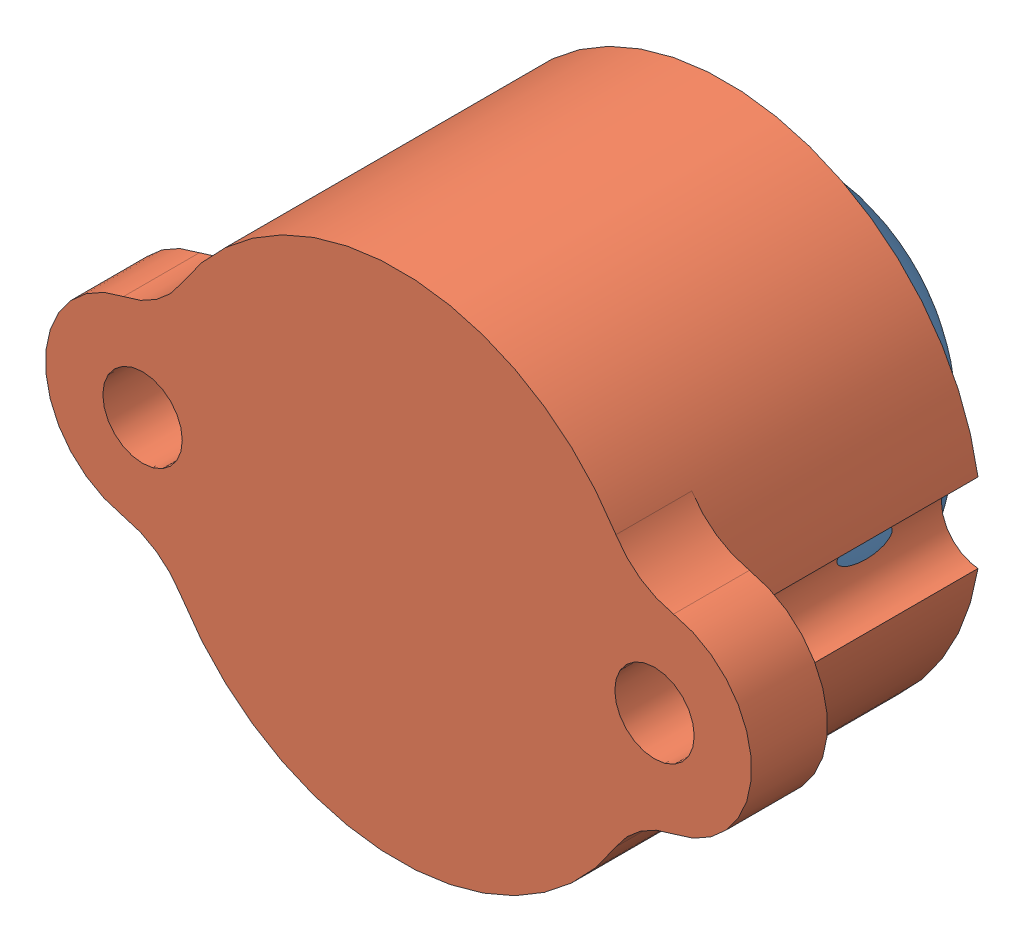
SolidWorks assembly sroller, configuration Default. Lengths in mm.
Overall size (20.32 14.73 13.46).
2 component instances, 2 part files, 1 mates.
Components (placement in the parent):
- boule scroller-1: boule scroller [Default] at (-35.481 -6.7783 23.3279) size (12.55 12.55 12.55)
- scroll_-1: scroll_ [Défaut] at (-35.481 -6.7783 21.1181) size (20.32 14.73 9.4)
Mates (geometry in assembly coordinates):
- Concentric1: concentric: sphere of boule scroller-1; sphere of scroll_-1
